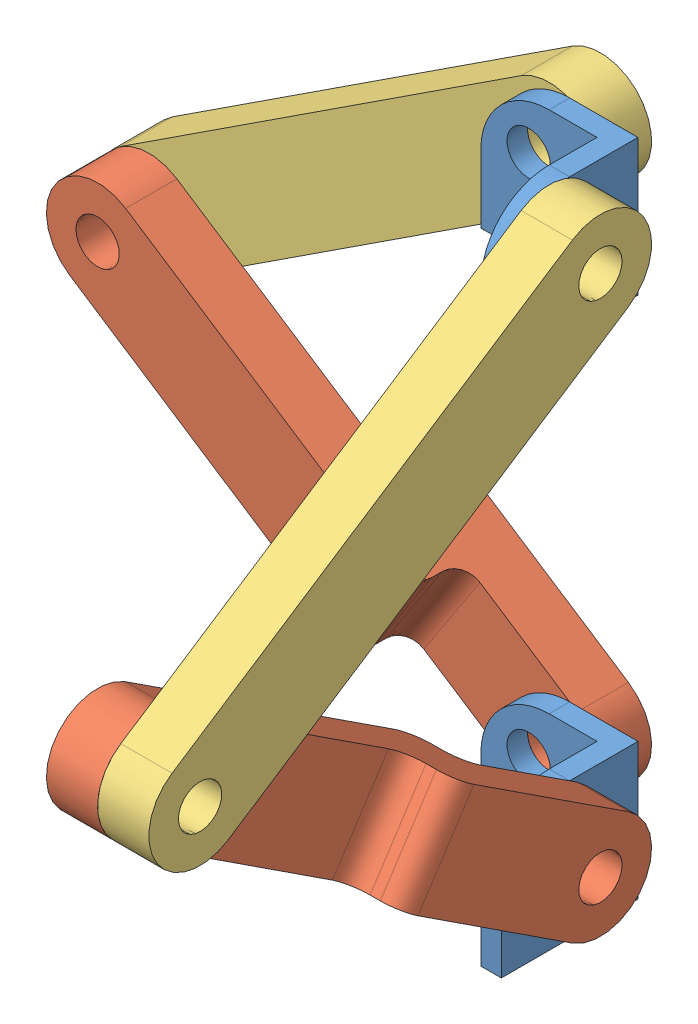
SolidWorks assembly tony idea rough, configuration Default. Lengths in mm.
Overall size (89.48 99.95 89.48).
6 component instances, 3 part files, 13 mates.
Components (placement in the parent):
- Part1-1: Part1 [Default] at (6.4041 -6.9458 1.3395) size (20 20 20)
- Part1-2: Part1 [Default] at (6.4041 69.6225 1.3395) size (20 20 20)
- link1-1: link1 [Default] at (-5.0959 6.0542 7.3395) x (-0.546917 -0.837187 0) z (0 0 -1) size (15 85 15)
- link1-2: link1 [Default] at (0.4041 6.0542 12.8395) x (0 0.837187 -0.546917) z (1 0 0) size (15 85 15)
- link2-1: link2 [Default] at (-63.699 44.3383 -7.6605) x (0.546917 -0.837187 0) z (0 0 1) size (15 85 7.5)
- link2-2: link2 [Default] at (7.9041 44.3383 71.4426) x (0 -0.837187 -0.546917) z (1 0 0) size (15 85 7.5)
Mates (geometry in assembly coordinates):
- Coincident7: coincident anti-aligned: plane of Part1-1 through (7.9041 13.0542 -0.1605) normal (1 0 0); plane of link1-2 through (7.9041 6.0542 12.8395) normal (-1 0 0)
- Concentric8: concentric anti-aligned: cylinder of Part1-1 through (-12.0959 6.0542 12.8395) axis (1 0 0) radius 3.175; cylinder of link1-2 through (15.4041 6.0542 12.8395) axis (-1 0 0) radius 3.175
- Coincident8: coincident anti-aligned: plane of link1-2 through (7.9041 44.3383 71.4426) normal (1 0 0); plane of link2-2 through (7.9041 82.6225 12.8395) normal (-1 0 0)
- Concentric9: concentric aligned: cylinder of link1-2 through (15.4041 44.3383 71.4426) axis (-1 0 0) radius 3.175; cylinder of link2-2 through (15.4041 44.3383 71.4426) axis (-1 0 0) radius 3.175
- Concentric10: concentric anti-aligned: cylinder of Part1-2 through (-12.0959 82.6225 12.8395) axis (1 0 0) radius 3.175; cylinder of link2-2 through (15.4041 82.6225 12.8395) axis (-1 0 0) radius 3.175
- Coincident9: coincident anti-aligned: plane of Part1-1 through (-12.0959 13.0542 -0.1605) normal (0 0 -1); plane of link1-1 through (-5.0959 6.0542 -0.1605) normal (0 0 1)
- Concentric11: concentric aligned: cylinder of Part1-1 through (-5.0959 6.0542 -0.1605) axis (0 0 1) radius 3.175; cylinder of link1-1 through (-5.0959 6.0542 -7.6605) axis (0 0 1) radius 3.175
- Coincident10: coincident anti-aligned: plane of link1-1 through (-63.699 44.3383 -0.1605) normal (0 0 -1); plane of link2-1 through (-5.0959 82.6225 -0.1605) normal (0 0 1)
- Concentric12: concentric anti-aligned: cylinder of link1-1 through (-63.699 44.3383 -7.6605) axis (0 0 1) radius 3.175; cylinder of link2-1 through (-63.699 44.3383 -0.1605) axis (0 0 -1) radius 3.175
- Concentric13: concentric anti-aligned: cylinder of Part1-2 through (-5.0959 82.6225 -0.1605) axis (0 0 1) radius 3.175; cylinder of link2-1 through (-5.0959 82.6225 -0.1605) axis (0 0 -1) radius 3.175
- Coincident11: coincident anti-aligned: plane of Part1-2 through (7.9041 89.6225 -0.1605) normal (1 0 0); plane of link2-2 through (7.9041 82.6225 12.8395) normal (-1 0 0)
- Coincident12: coincident anti-aligned: plane of Part1-2 through (-12.0959 89.6225 -0.1605) normal (0 0 -1); plane of link2-1 through (-5.0959 82.6225 -0.1605) normal (0 0 1)
- LimitAngle1: limit planar angle = 1.984239 rad aligned: plane of link2-2 through (15.4041 76.3436 8.7377) normal (0 -0.837187 -0.546917); plane of link1-2 through (15.4041 50.6172 67.3407) normal (0 0.837187 -0.546917)
